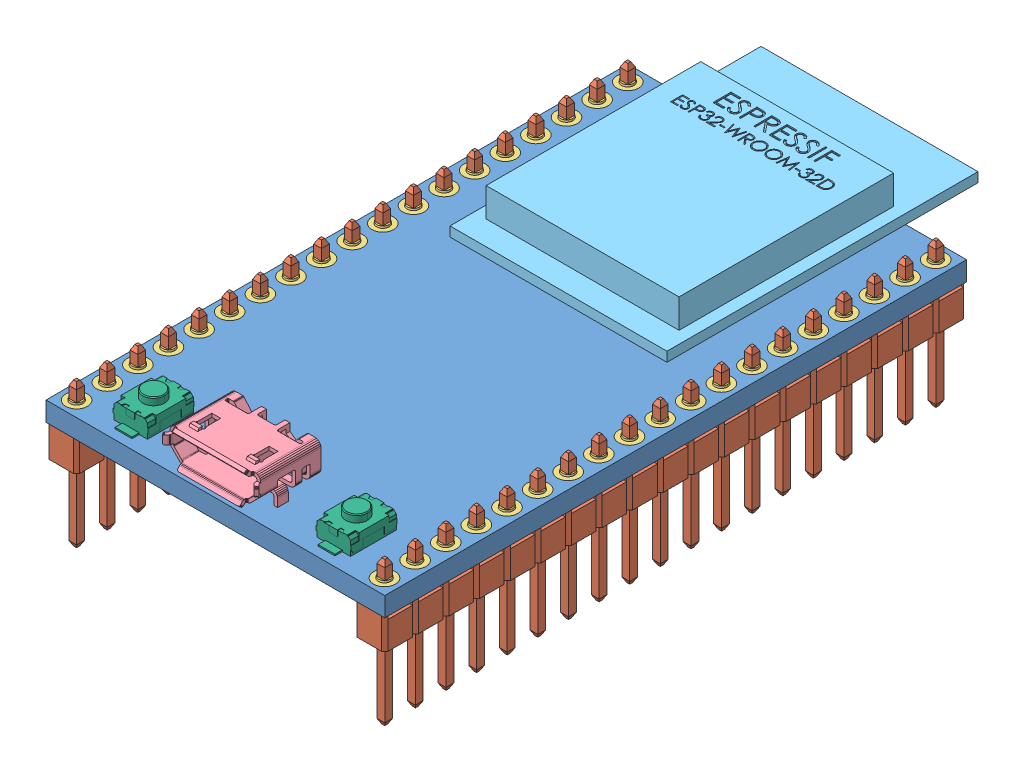
SolidWorks assembly ESP32-WROOM-32D, configuration 默认. Lengths in mm.
Overall size (28.1 14.23 54.86).
8 component instances, 6 part files, 0 mates.
Components (placement in the parent):
- Main-PCB.STEP-1: Main-PCB.STEP [默认] x (1 0 0) z (0 1 0) size (28.1 48.26 1.6)
- zl201-19_p2-54_l48-3_w2-54_h8-9.STEP-1: zl201-19_p2-54_l48-3_w2-54_h8-9.STEP [默认] at (-12.78 -0.25 22.86) x (0 0 1) z (0 -1 0) size (48.26 2.54 11.94)
- zl201-19_p2-54_l48-3_w2-54_h8-9.STEP-2: zl201-19_p2-54_l48-3_w2-54_h8-9.STEP [默认] at (12.78 -0.25 -22.86) x (0 0 -1) z (0 -1 0) size (48.26 2.54 11.94)
- Soldering-Contacts.STEP-1: Soldering-Contacts.STEP [默认] at (0 1.6 0) x (1 0 0) z (0 1 0) size (27.34 47.52 2)
- ab2_usb_micro_smd.wrl.STEP-1: ab2_usb_micro_smd.wrl.STEP [默认] at (0 2.585 24.73) x (1 0 0) z (0 1 0) size (8 5.6 3.57)
- ESP32-chip.STEP-1: ESP32-chip.STEP [默认] at (0 1.6 0) x (1 0 0) z (0 1 0) size (18 25.8 3.2)
- 3x4x2mm_tact_button.STEP-1: 3x4x2mm_tact_button.STEP [默认] at (9.1347 1.6 18.3459) x (0 0 1) z (-1 0 0) size (5 2 2.9)
- 3x4x2mm_tact_button.STEP-2: 3x4x2mm_tact_button.STEP [默认] at (-7.7053 1.6 18.3459) x (0 0 1) z (-1 0 0) size (5 2 2.9)
